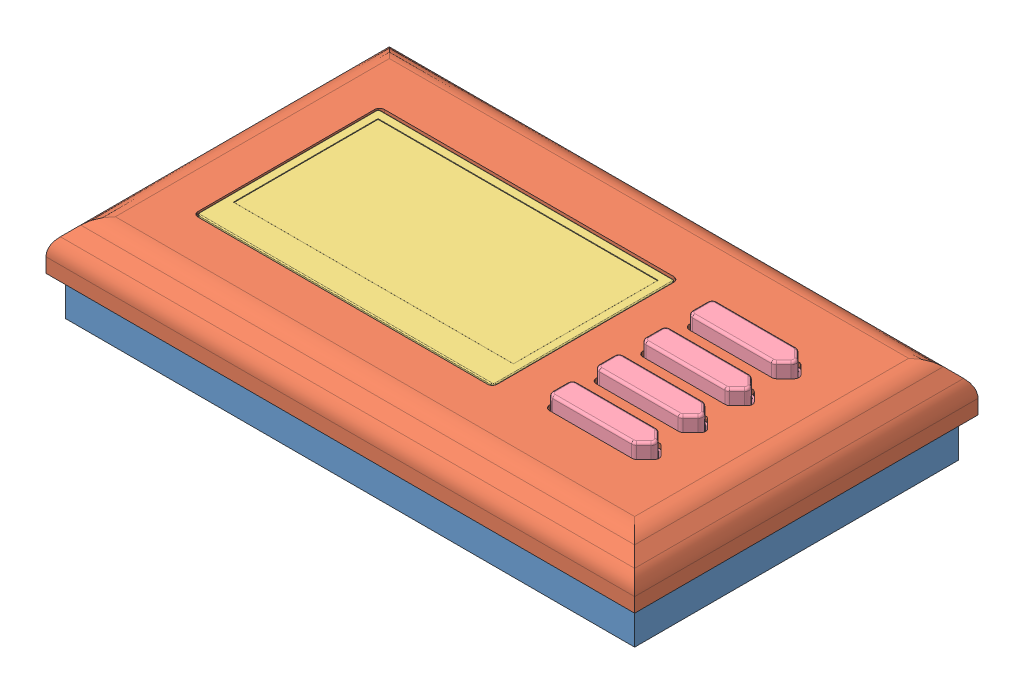
SolidWorks assembly Controller Assembly, configuration Default. Lengths in mm.
Overall size (120 20.7 70).
7 component instances, 4 part files, 9 mates.
Components (placement in the parent):
- Backing Piece-1: Backing Piece [Default] at origin size (116 10 66)
- Faceplate-1: Faceplate [Default] at (-2 8 2) size (120 10 70)
- Display-1: Display [Default] at (12.8177 16 -13.9274) size (60.5 2 37)
- Button-1: Button [Default] at (82.9677 16.7 -43.8331) size (21.39 5 6.8)
- Button-2: Button [Default] at (82.9677 16.7 -34.3331) size (21.39 5 6.8)
- Button-3: Button [Default] at (82.9677 16.7 -24.8331) size (21.39 5 6.8)
- Button-4: Button [Default] at (82.9677 16.7 -15.3331) size (21.39 5 6.8)
Mates (geometry in assembly coordinates):
- Width1: width aligned: plane of Display-1 through (12.8177 45.0543 -13.9274) normal (0 0 1); plane of Display-1 through (12.8177 45.0543 -50.9274) normal (0 0 -1); plane of Faceplate-1 through (12.5677 35.0543 -51.4274) normal (0 0 1); plane of Faceplate-1 through (12.5677 35.0543 -13.4274) normal (0 0 -1)
- Width2: width aligned: plane of Display-1 through (12.8177 45.0543 -13.9274) normal (-1 0 0); plane of Display-1 through (73.3177 45.0543 -13.9274) normal (1 0 0); plane of Faceplate-1 through (73.5677 35.0543 -51.4274) normal (-1 0 0); plane of Faceplate-1 through (12.5677 35.0543 -51.4274) normal (1 0 0)
- Coincident1: coincident aligned: plane of Faceplate-1 through (-2 45.0543 2) normal (0 1 0); plane of Display-1 through (12.8177 45.0543 -13.9274) normal (0 1 0)
- Width3: width anti-aligned: plane of Faceplate-1 through (82.5677 35.0543 -49.0831) normal (0 0 1); plane of Faceplate-1 through (82.5677 35.0543 -43.5831) normal (0 0 -1); plane of Button-1 through (82.9677 47.7543 -48.8331) normal (0 0 -1); plane of Button-1 through (82.9677 47.7543 -43.8331) normal (0 0 1)
- Distance1: distance = 0.4 mm anti-aligned: plane of Button-1 through (82.9677 20.7 -43.8331) normal (-1 0 0); plane of Faceplate-1 through (82.5677 8 -49.0831) normal (1 0 0)
- Distance3: distance = 0.1 mm anti-aligned: plane of Button-4 through (83.9677 16.7 -19.3331) normal (0 1 0); plane of Faceplate-1 through (100.4034 16.8 -19.5831) normal (0 -1 0)
- Width4: width aligned: plane of Backing Piece-1 through (0 10 -3) normal (0 0 -1); plane of Backing Piece-1 through (0 10 -63) normal (0 0 1); plane of Faceplate-1 through (-2 45.0543 0) normal (0 0 -1); plane of Faceplate-1 through (-2 45.0543 -66) normal (0 0 1)
- Width5: width anti-aligned: plane of Faceplate-1 through (116 45.0543 2) normal (-1 0 0); plane of Faceplate-1 through (0 45.0543 2) normal (1 0 0); plane of Backing Piece-1 through (116 10 0) normal (1 0 0); plane of Backing Piece-1 through (0 10 0) normal (-1 0 0)
- Coincident4: coincident anti-aligned: plane of Backing Piece-1 through (0 10 0) normal (0 1 0); plane of Faceplate-1 through (-2 10 2) normal (0 -1 0)
